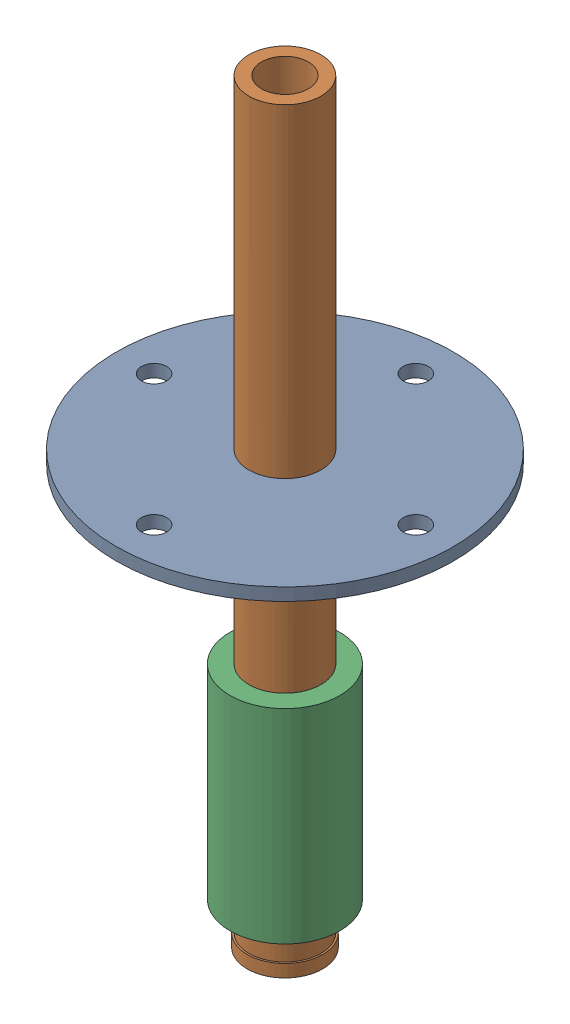
SolidWorks assembly steeringmechanism, configuration Default. Lengths in mm.
Overall size (134 300 134).
3 component instances, 3 part files, 3 mates.
Components (placement in the parent):
- chainringadapter-1: chainringadapter [Default] at (177.909 48.7159 -68.5742) size (134 5 134)
- steeringshaft-1: steeringshaft [Default] at (177.909 -117.6333 -68.5742) size (30 300 30)
- frame head tube-1: frame head tube [Default] at (177.909 -101.1333 -68.5742) size (43.6 89 43.6)
Mates (geometry in assembly coordinates):
- Coincident2: coincident anti-aligned: circle of chainringadapter-1; cylinder of steeringshaft-1 through (177.909 182.3667 -68.5742) axis (0 -1 0) radius 14.3
- Concentric1: concentric aligned: cylinder of steeringshaft-1 through (177.909 182.3667 -68.5742) axis (0 -1 0) radius 14.3; cylinder of frame head tube-1 through (177.909 -21.1333 -68.5742) axis (0 -1 0) radius 16.8
- Distance1: distance = 11.5 mm anti-aligned: plane of frame head tube-1 through (177.909 -101.1333 -68.5742) normal (0 -1 0); plane of steeringshaft-1 through (177.909 -112.6333 -68.5742) normal (0 1 0)
